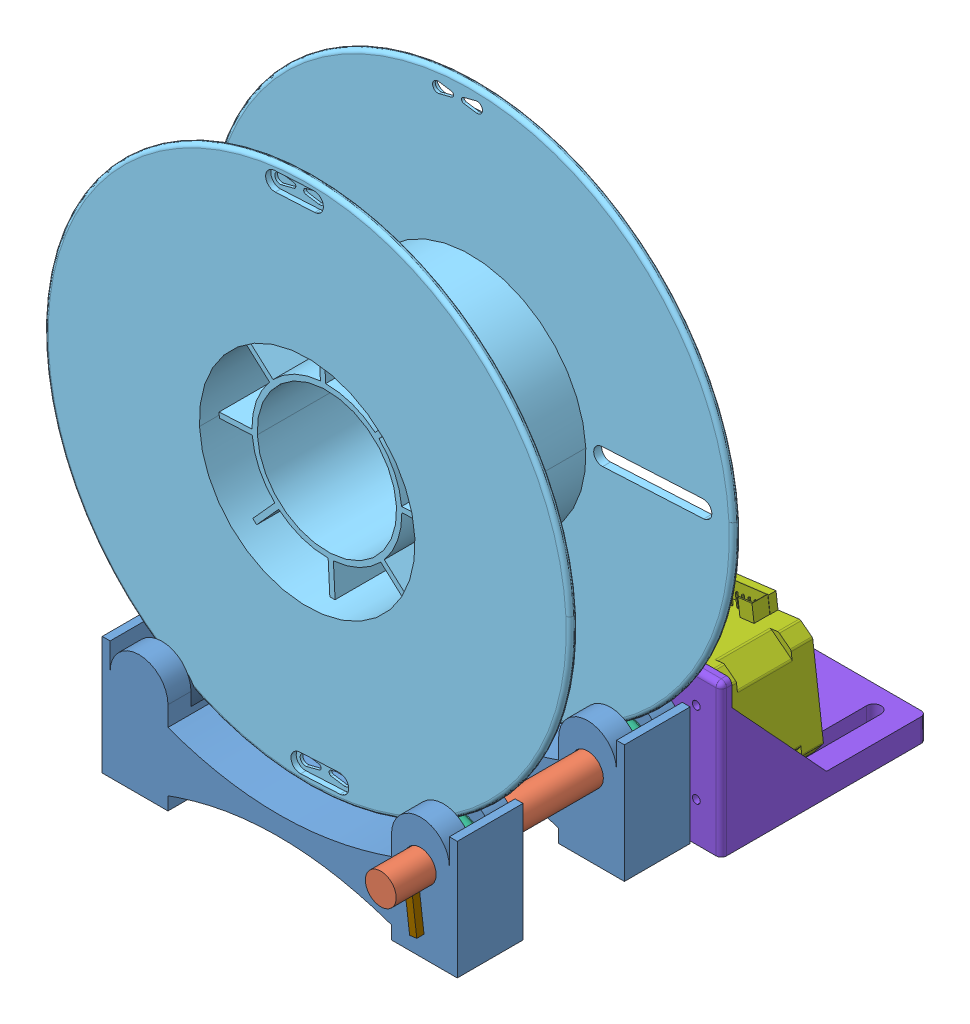
SolidWorks assembly Spooling sub-assembly, configuration Default. Lengths in mm.
Overall size (210.04 228.81 182.5).
53 component instances, 27 part files, 18 mates.
Components (placement in the parent):
- Spool Holder-1: Spool Holder [Default] at (114.0287 -4.056 45.1541) size (135 46 25)
- Spool Holder-2: Spool Holder [Default] at (114.0287 -4.056 -18.4114) size (135 46 25)
- Shaft for motor-1: Shaft for motor [Default] at (125.0426 25.8335 -39.746) x (0.992208 0.124596 0) z (0.124596 -0.992208 0) size (11.75 100 11.75)
- Ball Bearing 8 x 22 x 7mm-1: Ball Bearing 8 x 22 x 7mm [Default] at (18.0287 25.944 33.2041) x (0 0 1) z (-0.076409 0.997077 0) size (7 22 22)
  - 608-2RS Skate Board Ball Bearing.step-1: 608-2RS Skate Board Ball Bearing.step [Default] at origin size (7 22 22)
    - Ball 001.step-1: Ball 001.step [Default] at (0 0 7.5) size (4 4 4)
    - Ball 002.step-1: Ball 002.step [Default] at (0 5.8637 4.6762) x (1 0 0) z (0 0.781831 0.62349) size (4 4 4)
    - Ball 003.step-1: Ball 003.step [Default] at (0 7.312 -1.6689) x (1 0 0) z (0 0.974928 -0.222521) size (4 4 4)
    - Ball 004.step-1: Ball 004.step [Default] at (0 3.2541 -6.7573) x (1 0 0) z (0 0.433884 -0.900969) size (4 4 4)
    - Ball 005.step-1: Ball 005.step [Default] at (0 -3.2541 -6.7573) x (1 0 0) z (0 -0.433884 -0.900969) size (4 4 4)
    - Ball 006.step-1: Ball 006.step [Default] at (0 -7.312 -1.6689) x (1 0 0) z (0 -0.974928 -0.222521) size (4 4 4)
    - Ball 007.step-1: Ball 007.step [Default] at (0 -5.8637 4.6762) x (1 0 0) z (0 -0.781831 0.62349) size (4 4 4)
    - Outer Ring001.step-1: Outer Ring001.step [Default] at origin size (7 22 22)
    - Inner Ring001.step-1: Inner Ring001.step [Default] at origin size (7 12 12)
    - Seal 001.step-1: Seal 001.step [Default] at origin size (0.6 19 19)
    - Seal 002.step-1: Seal 002.step [Default] x (-1 0 0) z (0 0 -1) size (0.6 19 19)
    - Cage 001.step-1: Cage 001.step [Default] at origin size (2.31 17.85 17.41)
    - Cage clone 002.step-1: Cage clone 002.step [Default] x (-1 0 0) z (0 0 1) size (2.31 17.85 17.41)
    - Rivet 002.step-1: Rivet 002.step [Default] at (0 3.2541 6.7573) x (1 0 0) z (0 0.433884 0.900969) size (0.8 0.8 0.8)
    - Rivet 001.step-1: Rivet 001.step [Default] at (0 -3.2541 6.7573) x (1 0 0) z (0 -0.433884 0.900969) size (0.8 0.8 0.8)
    - Rivet 007.step-1: Rivet 007.step [Default] at (0 5.8637 -4.6762) x (1 0 0) z (0 0.781831 -0.62349) size (0.8 0.8 0.8)
    - Rivet 006.step-1: Rivet 006.step [Default] at (0 7.312 1.6689) x (1 0 0) z (0 0.974928 0.222521) size (0.8 0.8 0.8)
    - Rivet 005.step-1: Rivet 005.step [Default] at (0 -7.312 1.6689) x (1 0 0) z (0 -0.974928 0.222521) size (0.8 0.8 0.8)
    - Rivet 004.step-1: Rivet 004.step [Default] at (0 -5.8637 -4.6762) x (1 0 0) z (0 -0.781831 -0.62349) size (0.8 0.8 0.8)
    - Rivet 003.step-1: Rivet 003.step [Default] at (0 0 -7.5) x (1 0 0) z (0 0 -1) size (0.8 0.8 0.8)
- Ball Bearing 8 x 22 x 7mm-2: Ball Bearing 8 x 22 x 7mm [Default] at (18.0287 25.944 -30.3614) x (0 0 1) z (-1 0 0) size (7 22 22)
  - 608-2RS Skate Board Ball Bearing.step-1: 608-2RS Skate Board Ball Bearing.step [Default] at origin size (7 22 22)
    - Ball 001.step-1: Ball 001.step [Default] at (0 0 7.5) size (4 4 4)
    - Ball 002.step-1: Ball 002.step [Default] at (0 5.8637 4.6762) x (1 0 0) z (0 0.781831 0.62349) size (4 4 4)
    - Ball 003.step-1: Ball 003.step [Default] at (0 7.312 -1.6689) x (1 0 0) z (0 0.974928 -0.222521) size (4 4 4)
    - Ball 004.step-1: Ball 004.step [Default] at (0 3.2541 -6.7573) x (1 0 0) z (0 0.433884 -0.900969) size (4 4 4)
    - Ball 005.step-1: Ball 005.step [Default] at (0 -3.2541 -6.7573) x (1 0 0) z (0 -0.433884 -0.900969) size (4 4 4)
    - Ball 006.step-1: Ball 006.step [Default] at (0 -7.312 -1.6689) x (1 0 0) z (0 -0.974928 -0.222521) size (4 4 4)
    - Ball 007.step-1: Ball 007.step [Default] at (0 -5.8637 4.6762) x (1 0 0) z (0 -0.781831 0.62349) size (4 4 4)
    - Outer Ring001.step-1: Outer Ring001.step [Default] at origin size (7 22 22)
    - Inner Ring001.step-1: Inner Ring001.step [Default] at origin size (7 12 12)
    - Seal 001.step-1: Seal 001.step [Default] at origin size (0.6 19 19)
    - Seal 002.step-1: Seal 002.step [Default] x (-1 0 0) z (0 0 -1) size (0.6 19 19)
    - Cage 001.step-1: Cage 001.step [Default] at origin size (2.31 17.85 17.41)
    - Cage clone 002.step-1: Cage clone 002.step [Default] x (-1 0 0) z (0 0 1) size (2.31 17.85 17.41)
    - Rivet 002.step-1: Rivet 002.step [Default] at (0 3.2541 6.7573) x (1 0 0) z (0 0.433884 0.900969) size (0.8 0.8 0.8)
    - Rivet 001.step-1: Rivet 001.step [Default] at (0 -3.2541 6.7573) x (1 0 0) z (0 -0.433884 0.900969) size (0.8 0.8 0.8)
    - Rivet 007.step-1: Rivet 007.step [Default] at (0 5.8637 -4.6762) x (1 0 0) z (0 0.781831 -0.62349) size (0.8 0.8 0.8)
    - Rivet 006.step-1: Rivet 006.step [Default] at (0 7.312 1.6689) x (1 0 0) z (0 0.974928 0.222521) size (0.8 0.8 0.8)
    - Rivet 005.step-1: Rivet 005.step [Default] at (0 -7.312 1.6689) x (1 0 0) z (0 -0.974928 0.222521) size (0.8 0.8 0.8)
    - Rivet 004.step-1: Rivet 004.step [Default] at (0 -5.8637 -4.6762) x (1 0 0) z (0 -0.781831 -0.62349) size (0.8 0.8 0.8)
    - Rivet 003.step-1: Rivet 003.step [Default] at (0 0 -7.5) x (1 0 0) z (0 0 -1) size (0.8 0.8 0.8)
- esun spool-1: esun spool [Default] at (71.028 119.733 1.7195) x (0 0 1) z (-0.998672 -0.051512 0) size (65 200 200)
- 3D printed bearing ofr spooling system-1: 3D printed bearing ofr spooling system [Default] at (125.0287 25.944 30.4041) x (0 0 1) z (0.789788 -0.61338 0) size (6 22 22)
- 3D printed bearing ofr spooling system-2: 3D printed bearing ofr spooling system [Default] at (125.0287 25.944 -33.1614) x (0 0 1) z (-0.554271 -0.832336 0) size (6 22 22)
- nema 17 model v2-1: nema 17 model v2 [Default] at (125.0287 25.944 -85.4479) x (0.992208 0.124596 0) z (0 0 1) size (41.5 47.8 59.9)
- Motor holder for spool-1: Motor holder for spool [Default] at (108.0287 -4.056 -68.2479) x (-1 0 0) z (0 0 -1) size (53 57.35 78)
- Spool shaft connector-1: Spool shaft connector [Default] at (126.015 6.0509 50.254) x (0.992208 0.124596 0) z (0 0 1) size (2.75 20 2.75)
Mates (geometry in assembly coordinates):
- Parallel3: parallel aligned: plane of Part2-1 through (4.0287 -4.056 45.1541) normal (-1 0 0); plane of Part2-2 through (4.0287 -4.056 -18.4114) normal (-1 0 0)
- Concentric1: concentric aligned: cylinder of Part2-1 through (125.0287 25.944 45.1541) axis (0 0 -1) radius 6; cylinder of Part2-2 through (125.0287 25.944 -18.4114) axis (0 0 -1) radius 6
- Concentric2: concentric aligned: cylinder of Part2-1 through (18.0287 25.944 28.9041) axis (0 0 1) radius 11; cylinder of Ball Bearing 8 x 22 x 7mm-1/608-2RS Skate Board Ball Bearing.step-1/Outer Ring001.step-1 through (18.0287 25.944 29.7041) axis (0 0 1) radius 11
- Concentric3: concentric aligned: cylinder of Part2-2 through (18.0287 25.944 -34.6614) axis (0 0 1) radius 11; cylinder of Ball Bearing 8 x 22 x 7mm-2/608-2RS Skate Board Ball Bearing.step-1/Outer Ring001.step-1 through (18.0287 25.944 -33.8614) axis (0 0 1) radius 11
- Coincident9: coincident anti-aligned: plane of Part2-2 through (18.0287 25.944 -27.1614) normal (0 0 -1); circle of Ball Bearing 8 x 22 x 7mm-2/608-2RS Skate Board Ball Bearing.step-1/Outer Ring001.step-1
- Coincident10: coincident anti-aligned: plane of Part2-1 through (18.0287 25.944 36.4041) normal (0 0 -1); circle of Ball Bearing 8 x 22 x 7mm-1/608-2RS Skate Board Ball Bearing.step-1/Outer Ring001.step-1
- Parallel5: parallel anti-aligned: line of Part2-2 through (139.0287 -4.056 -43.4114) axis (-1 0 0); line of Motor holder for spool-1 through (99.0287 -4.056 -44.2479) axis (1 0 0)
- Concentric7: concentric aligned: circle of Part2-2; circle of Motor holder for spool-1
- Concentric8: concentric aligned: circle of nema 17 model v2-1; circle of Motor holder for spool-1
- Coincident15: coincident anti-aligned: plane of nema 17 model v2-1 through (125.0287 25.944 -48.2479) normal (0 0 1); plane of Motor holder for spool-1 through (150.0287 53.294 -48.2479) normal (0 0 -1)
- Coincident19: coincident anti-aligned: plane of Shaft for motor-1 through (123.2912 27.7416 -19.746) normal (0.124596 -0.992208 0); plane of nema 17 model v2-1 through (126.2678 28.1153 -25.5479) normal (-0.124596 0.992208 0)
- Coincident20: coincident: circle of Shaft for motor-1; cylinder of nema 17 model v2-1 through (125.0287 25.944 -50.2479) axis (0 0 1) radius 2.5
- Coincident23: coincident: plane of Shaft for motor-1 through (122.7928 31.7104 50.254) normal (0.992208 0.124596 0); plane of Spool shaft connector-1 through (123.5231 25.8951 50.254) normal (-0.992208 -0.124596 0)
- Coincident25: coincident: plane of Spool shaft connector-1 through (123.5231 25.8951 50.254) normal (0 0 1); plane of Shaft for motor-1 through (125.7694 32.0842 50.254) normal (0 0 -1)
- Concentric9: concentric anti-aligned: circle of Part2-1; circle of 3D printed bearing ofr spooling system-1
- Coincident27: coincident anti-aligned: plane of Part2-1 through (125.0287 25.944 36.4041) normal (0 0 -1); plane of 3D printed bearing ofr spooling system-1 through (116.341 32.6912 36.4041) normal (0 0 1)
- Concentric10: concentric anti-aligned: circle of Part2-2; circle of 3D printed bearing ofr spooling system-2
- Coincident29: coincident anti-aligned: plane of Part2-2 through (125.0287 25.944 -27.1614) normal (0 0 -1); plane of 3D printed bearing ofr spooling system-2 through (131.1257 35.0997 -27.1614) normal (0 0 1)
